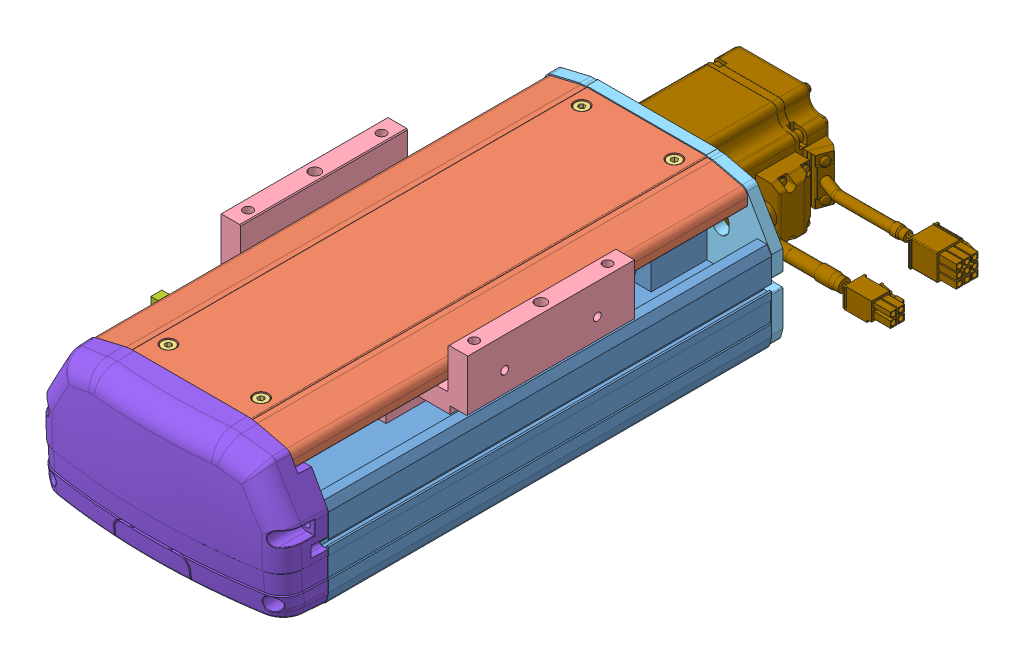
SolidWorks assembly S13-BC-200W, configuration 默认. Lengths in mm.
Overall size (199.7 78 340.96).
14 component instances, 9 part files, 40 mates.
Components (placement in the parent):
- S13-BC底座^S13-BC-200W-1: S13-BC底座^S13-BC-200W [默认] at origin size (135 66.2 262) (virtual)
- S13-BC上盖^S13-BC-200W-1: S13-BC上盖^S13-BC-200W [默认] at (0 60.35 123) size (109 12.5 246) (virtual)
- 内六角圆柱头螺钉M4×8[GB／T70．1-2000]^S13-BC-200W-1: 内六角圆柱头螺钉M4×8[GB／T70．1-2000]^S13-BC-200W [默认] at (-25 72.55 10) x (0 -1 0) z (-0.993621 0 -0.11277) size (12 7 7) (virtual)
- 内六角圆柱头螺钉M4×8[GB／T70．1-2000]^S13-BC-200W-2: 内六角圆柱头螺钉M4×8[GB／T70．1-2000]^S13-BC-200W [默认] at (25 72.55 10) x (0 -1 0) z (0.295931 0 -0.955209) size (12 7 7) (virtual)
- 内六角圆柱头螺钉M4×8[GB／T70．1-2000]^S13-BC-200W-3: 内六角圆柱头螺钉M4×8[GB／T70．1-2000]^S13-BC-200W [默认] at (-25 72.55 233) x (0 -1 0) z (0 0 1) size (12 7 7) (virtual)
- 内六角圆柱头螺钉M4×8[GB／T70．1-2000]^S13-BC-200W-4: 内六角圆柱头螺钉M4×8[GB／T70．1-2000]^S13-BC-200W [默认] at (25 72.55 233) x (0 -1 0) z (0 0 1) size (12 7 7) (virtual)
- S13-BC滑座^S13-BC-200W-1: S13-BC滑座^S13-BC-200W [默认] at (-1.3936 35.7784 73) size (133 62 90) (virtual)
- 复件 电机板S13-14-BC-60^S13-BC-200W-1: 复件 电机板S13-14-BC-60^S13-BC-200W [默认] at (0 1.7 -6) size (135 72.5 6) (virtual)
- 复件 外置感应片ST14-17^S13-BC-200W-1: 复件 外置感应片ST14-17^S13-BC-200W [默认] at (-67.5 55.4 118) x (0 0 1) z (-1 0 0) size (70 30.4 7.7) (virtual)
- 复件 光电开关EE-SX672^S13-BC-200W-1: 复件 光电开关EE-SX672^S13-BC-200W [默认] at (-67.5 19.4 102) x (0 0 1) z (-1 0 0) size (26 25 13) (virtual)
- 复件 光电开关EE-SX672^S13-BC-200W-2: 复件 光电开关EE-SX672^S13-BC-200W [默认] at (-67.5 19.4 128) x (0 0 1) z (-1 0 0) size (26 25 13) (virtual)
- 复件 光电开关EE-SX672^S13-BC-200W-3: 复件 光电开关EE-SX672^S13-BC-200W [默认] at (-67.5 19.4 181) x (0 0 1) z (-1 0 0) size (26 25 13) (virtual)
- 复件 13-14塑胶端盖 ^S13-BC-200W-1: 复件 13-14塑胶端盖 ^S13-BC-200W [默认] at (0 1 259) x (-1 0 0) z (0 0 -1) size (134.5 73.26 31.04) (virtual)
- 复件 复件 松下200W电机MHMF022L1U22^S13-BC-200W-1: 复件 复件 松下200W电机MHMF022L1U22^S13-BC-200W [默认] at (0 35.4 0) x (0 0 1) z (0 1 0) size (101 149.2 60) (virtual)
Mates (geometry in assembly coordinates):
- 重合169: coincident: plane of S13-BC上盖^S13-BC-200W-1 through (-25 68.55 10) normal (0 1 0); plane of 内六角圆柱头螺钉M4×8[GB／T70．1-2000]^S13-BC-200W-1 through (-25.3947 68.55 13.4777) normal (0 -1 0)
- 同心160: concentric: cylinder of 内六角圆柱头螺钉M4×8[GB／T70．1-2000]^S13-BC-200W-1 through (-25 72.55 10) axis (0 1 0) radius 3.5; cylinder of S13-BC上盖^S13-BC-200W-1 through (-25 68.55 10) axis (0 1 0) radius 4
- 同心161: concentric: cylinder of 内六角圆柱头螺钉M4×8[GB／T70．1-2000]^S13-BC-200W-2 through (25 72.55 10) axis (0 1 0) radius 3.5; cylinder of S13-BC上盖^S13-BC-200W-1 through (25 68.55 10) axis (0 1 0) radius 4
- 重合171: coincident: plane of S13-BC上盖^S13-BC-200W-1 through (25 68.55 10) normal (0 1 0); circle of 内六角圆柱头螺钉M4×8[GB／T70．1-2000]^S13-BC-200W-2
- 重合189: coincident: plane of S13-BC上盖^S13-BC-200W-1 through (25 68.55 233) normal (0 1 0); plane of 内六角圆柱头螺钉M4×8[GB／T70．1-2000]^S13-BC-200W-4 through (28.5 68.55 233) normal (0 -1 0)
- 同心192: concentric: cylinder of S13-BC上盖^S13-BC-200W-1 through (25 68.55 233) axis (0 1 0) radius 4; cylinder of 内六角圆柱头螺钉M4×8[GB／T70．1-2000]^S13-BC-200W-4 through (25 72.55 233) axis (0 1 0) radius 2
- 重合190: coincident: plane of S13-BC上盖^S13-BC-200W-1 through (-25 68.55 233) normal (0 1 0); plane of 内六角圆柱头螺钉M4×8[GB／T70．1-2000]^S13-BC-200W-3 through (-21.5 68.55 233) normal (0 -1 0)
- 同心193: concentric: cylinder of S13-BC上盖^S13-BC-200W-1 through (-25 68.55 233) axis (0 1 0) radius 4; cylinder of 内六角圆柱头螺钉M4×8[GB／T70．1-2000]^S13-BC-200W-3 through (-25 72.55 233) axis (0 1 0) radius 2
- 距离15: distance = 78 mm: plane of S13-BC滑座^S13-BC-200W-1 through (66.5 78 73) normal (0 1 0); plane of S13-BC底座^S13-BC-200W-1 through (-65.3076 0 262) normal (0 -1 0)
- 重合205: coincident: plane of S13-BC底座^S13-BC-200W-1 through (0 0 0) normal (1 0 0); plane of S13-BC上盖^S13-BC-200W-1 through (0 60.35 123) normal (1 0 0)
- 重合215: coincident: plane of S13-BC底座^S13-BC-200W-1 through (0 0 0) normal (0 0 1); plane of assembly through (0 0 0) normal (0 0 1)
- 重合216: coincident: plane of S13-BC底座^S13-BC-200W-1 through (0 0 0) normal (0 1 0); plane of assembly through (0 0 0) normal (0 1 0)
- 重合217: coincident: plane of S13-BC底座^S13-BC-200W-1 through (0 0 0) normal (1 0 0); plane of assembly through (0 0 0) normal (1 0 0)
- 宽度2: width: plane of S13-BC底座^S13-BC-200W-1 through (67.5 43.6699 262) normal (1 0 0); plane of S13-BC底座^S13-BC-200W-1 through (-67.5 43.6699 262) normal (-1 0 0); plane of S13-BC滑座^S13-BC-200W-1 through (-66.5 16 176.9386) normal (-1 0 0); plane of S13-BC滑座^S13-BC-200W-1 through (66.5 16 171.2654) normal (1 0 0)
- 同心202: concentric: cylinder of S13-BC底座^S13-BC-200W-1 through (-62.5 39.5 262) axis (0 0 -1) radius 1.5; cylinder of 复件 13-14塑胶端盖 ^S13-BC-200W-1 through (-62.5 39.5 239) axis (0 0 -1) radius 2.1
- 宽度3: width: plane of S13-BC底座^S13-BC-200W-1 through (-67.5 12 262) normal (-1 0 0); plane of S13-BC底座^S13-BC-200W-1 through (67.5 12 262) normal (1 0 0); plane of 复件 13-14塑胶端盖 ^S13-BC-200W-1 through (67.25 46.7626 239) normal (-0.999048 0 -0.043619); plane of 复件 13-14塑胶端盖 ^S13-BC-200W-1 through (-67.25 2.8914 239) normal (0.999048 0 -0.043619)
- 重合225: coincident: plane of S13-BC底座^S13-BC-200W-1 through (-73.3212 -9 239) normal (0 0 1); plane of 复件 13-14塑胶端盖 ^S13-BC-200W-1 through (0 1 239) normal (0 0 1)
- 距离24: distance = 0.9 mm: plane of 复件 电机板S13-14-BC-60^S13-BC-200W-1 through (-64.8855 0.9 0) normal (0 -1 0); plane of S13-BC底座^S13-BC-200W-1 through (-65.3076 0 262) normal (0 -1 0)
- 重合227: coincident: plane of S13-BC底座^S13-BC-200W-1 through (-56.7 26.5 0) normal (0 0 -1); plane of 复件 电机板S13-14-BC-60^S13-BC-200W-1 through (64.4731 2.9 0) normal (0 0 1)
- 宽度4: width: plane of 复件 电机板S13-14-BC-60^S13-BC-200W-1 through (67.5 6.7616 0) normal (1 0 0); plane of 复件 电机板S13-14-BC-60^S13-BC-200W-1 through (-67.5 6.7616 0) normal (-1 0 0); plane of S13-BC底座^S13-BC-200W-1 through (67.5 12 262) normal (1 0 0); plane of S13-BC底座^S13-BC-200W-1 through (-67.5 12 262) normal (-1 0 0)
- 同心208: concentric: cylinder of S13-BC滑座^S13-BC-200W-1 through (-67 61.4 93) axis (-1 0 0) radius 2.1; cylinder of 复件 外置感应片ST14-17^S13-BC-200W-1 through (-67.5 61.4 93) axis (-1 0 0) radius 2.55
- 同心209: concentric: cylinder of S13-BC滑座^S13-BC-200W-1 through (-67 61.4 143) axis (-1 0 0) radius 2.1; cylinder of 复件 外置感应片ST14-17^S13-BC-200W-1 through (-67.5 61.4 143) axis (-1 0 0) radius 2.55
- 重合234: coincident: plane of S13-BC滑座^S13-BC-200W-1 through (-66.5 16 176.9386) normal (-1 0 0); plane of 复件 外置感应片ST14-17^S13-BC-200W-1 through (-66.5 55.4 118) normal (1 0 0)
- 重合237: coincident: plane of S13-BC上盖^S13-BC-200W-1 through (50.5 64.6864 0) normal (0 0 -1); plane of 复件 电机板S13-14-BC-60^S13-BC-200W-1 through (64.4731 2.9 0) normal (0 0 1)
- 距离29: distance = 0.55 mm: plane of 复件 电机板S13-14-BC-60^S13-BC-200W-1 through (32.2972 73.4 0) normal (0 1 0); plane of S13-BC上盖^S13-BC-200W-1 through (-32 72.85 246) normal (0 1 0)
- 距离30: distance = 19.4 mm: plane of 复件 光电开关EE-SX672^S13-BC-200W-1 through (-80.5 19.4 102) normal (0 -1 0); plane of S13-BC底座^S13-BC-200W-1 through (32 0 262) normal (0 -1 0)
- 重合239: coincident: plane of S13-BC底座^S13-BC-200W-1 through (-67.5 43.6699 262) normal (-1 0 0); plane of 复件 光电开关EE-SX672^S13-BC-200W-1 through (-67.5 44.4 102) normal (1 0 0)
- 距离31: distance = 100 mm: plane of 复件 光电开关EE-SX672^S13-BC-200W-1 through (-80.5 19.4 102) normal (0 0 -1); plane of S13-BC底座^S13-BC-200W-1 through (-56.7 26.5 0) normal (0 0 -1)
- 重合241: coincident: plane of 复件 光电开关EE-SX672^S13-BC-200W-1 through (-80.5 44.4 102) normal (-1 0 0); plane of 复件 光电开关EE-SX672^S13-BC-200W-2 through (-80.5 44.4 128) normal (-1 0 0)
- 重合242: coincident: plane of 复件 光电开关EE-SX672^S13-BC-200W-1 through (-80.5 19.4 102) normal (0 -1 0); plane of 复件 光电开关EE-SX672^S13-BC-200W-2 through (-80.5 19.4 128) normal (0 -1 0)
- 重合243: coincident: plane of 复件 光电开关EE-SX672^S13-BC-200W-1 through (-70 32.4 118) normal (0 0 1); plane of 复件 光电开关EE-SX672^S13-BC-200W-2 through (-70 32.4 118) normal (0 0 -1)
- 重合245: coincident: plane of 复件 光电开关EE-SX672^S13-BC-200W-2 through (-80.5 19.4 128) normal (0 -1 0); plane of 复件 光电开关EE-SX672^S13-BC-200W-3 through (-80.5 19.4 181) normal (0 -1 0)
- 重合246: coincident: plane of S13-BC底座^S13-BC-200W-1 through (-67.5 43.6699 262) normal (-1 0 0); plane of 复件 光电开关EE-SX672^S13-BC-200W-3 through (-67.5 44.4 181) normal (1 0 0)
- 重合247: coincident: plane of 复件 光电开关EE-SX672^S13-BC-200W-2 through (-80.5 19.4 128) normal (0 -1 0); plane of 复件 光电开关EE-SX672^S13-BC-200W-3 through (-80.5 19.4 181) normal (0 -1 0)
- 距离32: distance = 52 mm: plane of 复件 光电开关EE-SX672^S13-BC-200W-3 through (-80.5 19.4 187) normal (0 0 1); plane of S13-BC底座^S13-BC-200W-1 through (-73.3212 -9 239) normal (0 0 1)
- 同心210: concentric: cylinder of S13-BC底座^S13-BC-200W-1 through (0 35.4 100.7107) axis (0 0 -1) radius 25; cylinder of 复件 复件 松下200W电机MHMF022L1U22^S13-BC-200W-1 through (0 35.4 30) axis (0 0 -1) radius 5.5
- 平行1: parallel: plane of S13-BC底座^S13-BC-200W-1 through (-67.5 43.6699 262) normal (-1 0 0); plane of 复件 复件 松下200W电机MHMF022L1U22^S13-BC-200W-1 through (-30 60.4 -54.5) normal (-1 0 0)
- 重合249: coincident: plane of S13-BC底座^S13-BC-200W-1 through (-56.7 26.5 0) normal (0 0 -1); plane of 复件 复件 松下200W电机MHMF022L1U22^S13-BC-200W-1 through (25 60.4 0) normal (0 0 1)
- 距离33: distance = 124 mm: cylinder of S13-BC滑座^S13-BC-200W-1 through (-61 78 118) axis (0 1 0) radius 3; plane of 复件 电机板S13-14-BC-60^S13-BC-200W-1 through (64.4731 2.9 -6) normal (0 0 -1)
- 宽度5: width: plane of 复件 光电开关EE-SX672^S13-BC-200W-1 through (-80.5 19.4 108) normal (0 0 1); plane of 复件 光电开关EE-SX672^S13-BC-200W-2 through (-80.5 19.4 128) normal (0 0 -1); plane of 复件 外置感应片ST14-17^S13-BC-200W-1 through (-74.2 53.4 125.5) normal (0 0 1); plane of 复件 外置感应片ST14-17^S13-BC-200W-1 through (-74.2 38 110.5) normal (0 0 -1)
